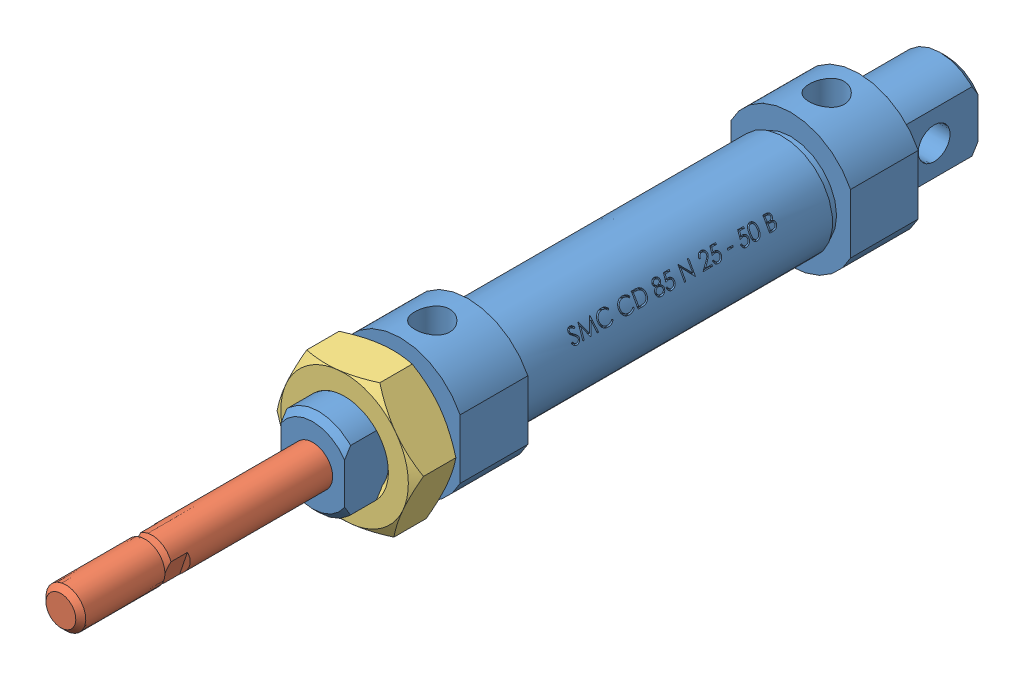
SolidWorks assembly Assem Cylinder SMC CD 85N25-50B, configuration Default. Lengths in mm.
Overall size (47.67 48.73 222.21).
3 component instances, 3 part files, 7 mates.
Components (placement in the parent):
- Corpo SMC C 85 25-50-1: Corpo SMC C 85 25-50 [Default] at (0 0 22) size (30 33.5 159)
- Stelo SMC C 85-1: Stelo SMC C 85 [Default] at (0 0 63.2105) x (-0.322296 -0.946639 0) z (0 0 1) size (15 15 132)
- Dado Cylinder SMC C85 N25-1: Dado Cylinder SMC C85 N25 [M22] at (0 0 8.5) x (0 0 -1) z (0.592644 -0.805465 0) size (11 32 36.95)
Mates (geometry in assembly coordinates):
- Coincidente1: coincident aligned: plane of Corpo SMC C 85 25-50-1 through (0 0 22) normal (0 1 0); plane of assembly through (0 0 0) normal (0 1 0)
- Coincidente2: coincident aligned: plane of Corpo SMC C 85 25-50-1 through (0 0 22) normal (1 0 0); plane of assembly through (0 0 0) normal (1 0 0)
- Coincidente3: coincident aligned: plane of Corpo SMC C 85 25-50-1 through (0 11 0) normal (0 0 1); plane of assembly through (0 0 0) normal (0 0 1)
- Coincidente4: coincident anti-aligned: line of Corpo SMC C 85 25-50-1 through (0 0 32.7554) axis (0 0 -1); line of Stelo SMC C 85-1 through (0 0 20.1105) axis (0 0 1)
- DistanzaLimite1: limit distance = 35.2105 mm aligned: plane of Stelo SMC C 85-1 through (0 0 63.2105) normal (0 0 1); plane of Corpo SMC C 85 25-50-1 through (0 0 28) normal (0 0 1)
- Concentrico1: concentric anti-aligned: cylinder of Corpo SMC C 85 25-50-1 through (0 0 22) axis (0 0 -1) radius 11; cylinder of Dado Cylinder SMC C85 N25-1 through (0 0 3) axis (0 0 1) radius 9.5
- Distanza1: distance = 3 mm anti-aligned: plane of Corpo SMC C 85 25-50-1 through (0 11 0) normal (0 0 1); plane of Dado Cylinder SMC C85 N25-1 through (-18.362 -2.0417 3) normal (0 0 -1)
